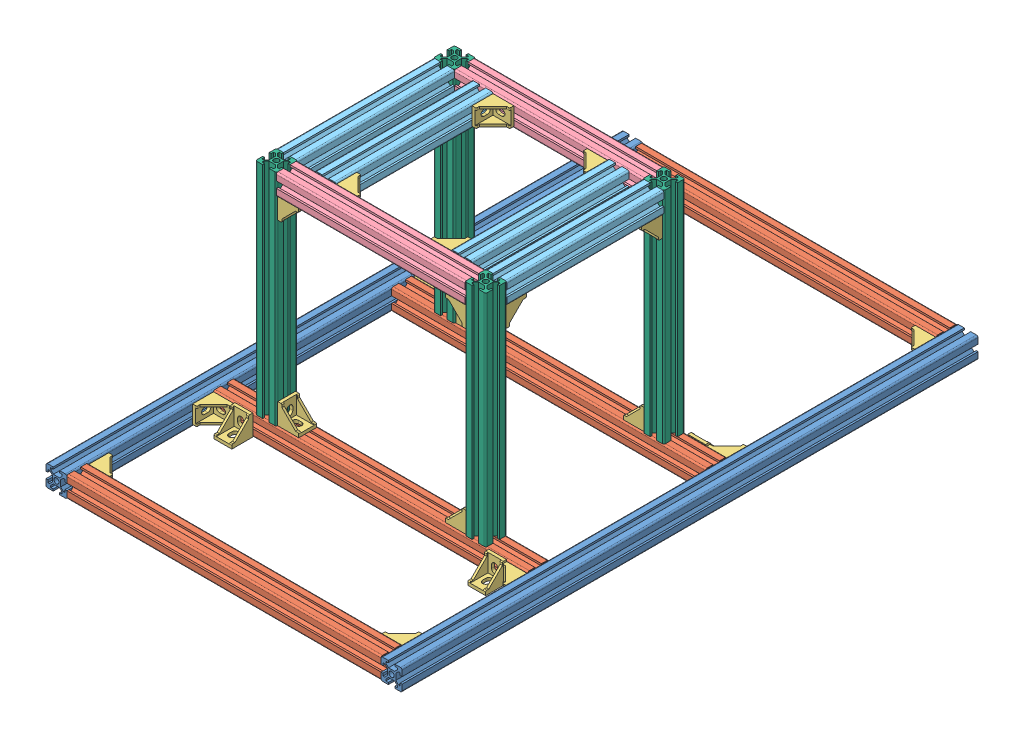
SolidWorks assembly 外框架, configuration 默认. Lengths in mm.
Overall size (340 230 550).
44 component instances, 6 part files, 128 mates.
Components (placement in the parent):
- 20x20-550mm-1: 20x20-550mm [默认] at (125.4634 0 -275) x (-1 0 0) z (0 0 -1) size (20 20 550)
- 20x20-550mm-2: 20x20-550mm [默认] at (-194.5366 0 -275) x (-1 0 0) z (0 0 -1) size (20 20 550)
- 20x20-300mm-1: 20x20-300mm [默认] at (115.4634 0 -265) x (0 0 -1) z (1 0 0) size (20 20 300)
- 20x20-300mm-2: 20x20-300mm [默认] at (115.4634 0 265) x (0 0 -1) z (1 0 0) size (20 20 300)
- 20x20-300mm-4: 20x20-300mm [默认] at (115.4634 0 125) x (0 0 -1) z (1 0 0) size (20 20 300)
- 20x20-300mm-5: 20x20-300mm [默认] at (115.4634 0 -45) x (0 0 -1) z (1 0 0) size (20 20 300)
- 2020 Corner pieces-1: 2020 Corner pieces [默认] at (55.4634 190 -44.8) x (0 0 1) z (0 -1 0) size (17 20 20)
- 2020-210mm-1: 2020-210mm [默认] at (-124.5366 210 -45) x (0 0 1) z (-1 0 0) size (20 20 180)
- 20x20-150mm-1: 20x20-150mm [默认] at (-134.5366 210 -35) x (0 1 0) z (0 0 -1) size (20 20 150)
- 2020 Corner pieces-2: 2020 Corner pieces [默认] at (-124.5366 190 -44.8) x (0 0 -1) z (0 -1 0) size (17 20 20)
- 2020 Corner pieces-3: 2020 Corner pieces [默认] at (-134.3366 190 -35) x (1 0 0) z (0 -1 0) size (17 20 20)
- 2020 Corner pieces-4: 2020 Corner pieces [默认] at (-134.3366 190 115) x (-1 0 0) z (0 -1 0) size (17 20 20)
- 2020 Corner pieces-5: 2020 Corner pieces [默认] at (-124.5366 190 125.2) x (0 0 -1) z (0 -1 0) size (17 20 20)
- 2020-210mm-2: 2020-210mm [默认] at (-124.5366 210 125) x (0 0 1) z (-1 0 0) size (20 20 180)
- 2020 Corner pieces-6: 2020 Corner pieces [默认] at (55.4634 190 125.2) x (0 0 1) z (0 -1 0) size (17 20 20)
- 2020 Corner pieces-7: 2020 Corner pieces [默认] at (65.6634 190 115) x (-1 0 0) z (0 -1 0) size (17 20 20)
- 20x20-150mm-2: 20x20-150mm [默认] at (65.4634 210 -35) x (0 1 0) z (0 0 -1) size (20 20 150)
- 2020 Corner pieces-8: 2020 Corner pieces [默认] at (65.6634 190 -35) x (1 0 0) z (0 -1 0) size (17 20 20)
- 2020 Corner pieces-9: 2020 Corner pieces [默认] at (45.4634 10 125.2) x (0 0 1) z (-1 0 0) size (17 20 20)
- 2020 Corner pieces-10: 2020 Corner pieces [默认] at (45.4634 10 -44.8) x (0 0 1) z (-1 0 0) size (17 20 20)
- 2020 Corner pieces-11: 2020 Corner pieces [默认] at (115.4634 -0.2 -65) x (0 -1 0) z (0 0 -1) size (17 20 20)
- 2020 Corner pieces-12: 2020 Corner pieces [默认] at (-124.5366 20 125.2) x (0 0 1) z (0 1 0) size (17 20 20)
- 2020 Corner pieces-13: 2020 Corner pieces [默认] at (115.4634 -0.2 145) x (0 1 0) z (0 0 1) size (17 20 20)
- 2020 Corner pieces-14: 2020 Corner pieces [默认] at (-184.5366 -0.2 -65) x (0 1 0) z (0 0 -1) size (17 20 20)
- 2020 Corner pieces-15: 2020 Corner pieces [默认] at (-124.5366 20 -44.8) x (0 0 1) z (0 1 0) size (17 20 20)
- 2020 Corner pieces-16: 2020 Corner pieces [默认] at (-184.5366 -0.2 -245) x (0 -1 0) z (0 0 1) size (17 20 20)
- 2020 Corner pieces-17: 2020 Corner pieces [默认] at (105.4634 0.2 -255) x (0 -1 0) z (-1 0 0) size (17 20 20)
- 20x20-150mm-3: 20x20-150mm [默认] at (32.3019 210 -35) x (1 0 0) z (0 0 -1) size (20 20 150)
- 2020 Corner pieces-18: 2020 Corner pieces [默认] at (12.3019 209.8 115) x (0 1 0) z (-1 0 0) size (17 20 20)
- 2020 Corner pieces-19: 2020 Corner pieces [默认] at (12.3019 209.8 -35) x (0 -1 0) z (-1 0 0) size (17 20 20)
- 20x20-150mm-4: 20x20-150mm [默认] at (-97.6981 210 -35) x (-1 0 0) z (0 0 -1) size (20 20 150)
- 2020 Corner pieces-20: 2020 Corner pieces [默认] at (-77.6981 210.2 115) x (0 -1 0) z (1 0 0) size (17 20 20)
- 2020 Corner pieces-21: 2020 Corner pieces [默认] at (-77.6981 210.2 -35) x (0 1 0) z (1 0 0) size (17 20 20)
- 2020 Corner pieces-22: 2020 Corner pieces [默认] at (-155.5864 -10 -65) x (-1 0 0) z (0 0 -1) size (17 20 20)
- 2020 Corner pieces-23: 2020 Corner pieces [默认] at (-155.5864 -10 145) size (17 20 20)
- 2020 Corner pieces-24: 2020 Corner pieces [默认] at (86.8158 -10 145) size (17 20 20)
- 2020 Corner pieces-25: 2020 Corner pieces [默认] at (-184.5366 -0.2 245) x (0 1 0) z (0 0 -1) size (17 20 20)
- 2020 Corner pieces-26: 2020 Corner pieces [默认] at (105.4634 -0.2 255) x (0 1 0) z (-1 0 0) size (17 20 20)
- 2020 Corner pieces-27: 2020 Corner pieces [默认] at (86.8158 -10 -65) x (-1 0 0) z (0 0 -1) size (17 20 20)
- 2020 Corner pieces-28: 2020 Corner pieces [默认] at (-184.5366 0.2 145) x (0 -1 0) z (0 0 1) size (17 20 20)
- 20x20-250mm-1: 20x20-250mm [默认] at (65.4634 220 125) x (0 0 -1) z (0 1 0) size (20 20 210)
- 20x20-250mm-2: 20x20-250mm [默认] at (-134.5366 220 125) x (1 0 0) z (0 1 0) size (20 20 210)
- 20x20-250mm-3: 20x20-250mm [默认] at (65.4634 220 -45) x (1 0 0) z (0 1 0) size (20 20 210)
- 20x20-250mm-4: 20x20-250mm [默认] at (-134.5366 220 -45) x (1 0 0) z (0 1 0) size (20 20 210)
Mates (geometry in assembly coordinates):
- 重合1: coincident anti-aligned: plane of 20x20-550mm-1 through (115.4634 -8.5 275) normal (-1 0 0); plane of 20x20-300mm-1 through (115.4634 -8.5 -273.5) normal (1 0 0)
- 重合2: coincident aligned: plane of 20x20-550mm-1 through (133.9634 10 275) normal (0 1 0); plane of 20x20-300mm-1 through (-184.5366 10 -256.5) normal (0 1 0)
- 重合3: coincident anti-aligned: plane of 20x20-550mm-2 through (-184.5366 3.1 275) normal (1 0 0); plane of 20x20-300mm-1 through (-184.5366 -8.5 -273.5) normal (-1 0 0)
- 重合4: coincident aligned: plane of 20x20-550mm-2 through (-186.0366 10 275) normal (0 1 0); plane of 20x20-300mm-1 through (-184.5366 10 -268.1) normal (0 1 0)
- 重合5: coincident aligned: plane of 20x20-550mm-2 through (-203.0366 -8.5 -275) normal (0 0 -1); plane of 20x20-300mm-1 through (-184.5366 -8.5 -275) normal (0 0 -1)
- 重合6: coincident aligned: plane of 20x20-550mm-1 through (116.9634 -8.5 -275) normal (0 0 -1); plane of 20x20-550mm-2 through (-203.0366 -8.5 -275) normal (0 0 -1)
- 重合7: coincident anti-aligned: plane of 20x20-550mm-1 through (115.4634 -8.5 275) normal (-1 0 0); plane of 20x20-300mm-5 through (115.4634 -8.5 -133.5) normal (1 0 0)
- 重合8: coincident aligned: plane of 20x20-300mm-1 through (-184.5366 10 -256.5) normal (0 1 0); plane of 20x20-300mm-5 through (-184.5366 10 -128.1) normal (0 1 0)
- 重合9: coincident anti-aligned: plane of 20x20-550mm-1 through (115.4634 -8.5 275) normal (-1 0 0); plane of 20x20-300mm-2 through (115.4634 -8.5 256.5) normal (1 0 0)
- 重合10: coincident aligned: plane of 20x20-300mm-2 through (-184.5366 10 273.5) normal (0 1 0); plane of 20x20-300mm-5 through (-184.5366 10 -116.5) normal (0 1 0)
- 重合11: coincident anti-aligned: plane of 20x20-550mm-1 through (115.4634 -8.5 275) normal (-1 0 0); plane of 20x20-300mm-4 through (115.4634 -8.5 36.5) normal (1 0 0)
- 重合12: coincident aligned: plane of 20x20-550mm-1 through (122.3634 10 275) normal (0 1 0); plane of 20x20-300mm-4 through (-184.5366 10 53.5) normal (0 1 0)
- 重合13: coincident aligned: plane of 20x20-550mm-1 through (116.9634 -8.5 275) normal (0 0 1); plane of 20x20-300mm-2 through (-184.5366 -8.5 275) normal (0 0 1)
- 重合22: coincident anti-aligned: plane of 2020 Corner pieces-1 through (35.4634 200 -133.3) normal (0 1 0); plane of 2020-210mm-1 through (55.4634 200 -121.9) normal (0 -1 0)
- 重合23: coincident aligned: plane of 2020 Corner pieces-1 through (55.4634 190 -124.8) normal (1 0 0); plane of 2020-210mm-1 through (55.4634 201.5 -116.5) normal (1 0 0)
- 重合24: coincident anti-aligned: plane of 2020-210mm-1 through (55.4634 200 -133.5) normal (0 -1 0); plane of 2020 Corner pieces-2 through (-104.5366 200 -116.3) normal (0 1 0)
- 重合25: coincident aligned: plane of 2020-210mm-1 through (-124.5366 201.5 -116.5) normal (-1 0 0); plane of 2020 Corner pieces-2 through (-124.5366 190 -124.8) normal (-1 0 0)
- 重合26: coincident anti-aligned: plane of 20x20-150mm-1 through (-131.4366 200 35) normal (0 -1 0); plane of 2020 Corner pieces-4 through (-125.8366 200 15) normal (0 1 0)
- 重合27: coincident aligned: plane of 20x20-150mm-1 through (-143.0366 218.5 35) normal (0 0 1); plane of 2020 Corner pieces-4 through (-134.3366 190 35) normal (0 0 1)
- 重合28: coincident aligned: plane of 20x20-150mm-1 through (-131.4366 201.8 35) normal (-1 0 0); plane of 2020 Corner pieces-4 through (-131.4366 200 26.5) normal (-1 0 0)
- 重合29: coincident anti-aligned: plane of 20x20-150mm-1 through (-131.4366 200 35) normal (0 -1 0); plane of 2020 Corner pieces-3 through (-142.8366 200 -95) normal (0 1 0)
- 重合30: coincident aligned: plane of 20x20-150mm-1 through (-143.0366 218.5 -115) normal (0 0 -1); plane of 2020 Corner pieces-3 through (-134.3366 190 -115) normal (0 0 -1)
- 重合31: coincident aligned: plane of 20x20-150mm-1 through (-131.4366 201.8 35) normal (-1 0 0); plane of 2020 Corner pieces-3 through (-131.4366 200 -103.5) normal (-1 0 0)
- 重合32: coincident aligned: plane of 2020-210mm-2 through (55.4634 201.5 53.5) normal (1 0 0); plane of 2020 Corner pieces-6 through (55.4634 190 45.2) normal (1 0 0)
- 重合33: coincident anti-aligned: plane of 2020-210mm-2 through (55.4634 200 48.1) normal (0 -1 0); plane of 2020 Corner pieces-6 through (35.4634 200 36.7) normal (0 1 0)
- 重合34: coincident anti-aligned: plane of 2020 Corner pieces-5 through (-104.5366 200 53.7) normal (0 1 0); plane of 2020-210mm-2 through (55.4634 200 36.5) normal (0 -1 0)
- 重合35: coincident aligned: plane of 2020 Corner pieces-5 through (-124.5366 190 45.2) normal (-1 0 0); plane of 2020-210mm-2 through (-124.5366 201.5 53.5) normal (-1 0 0)
- 重合36: coincident aligned: plane of 2020 Corner pieces-7 through (68.5634 200 26.5) normal (-1 0 0); plane of 20x20-150mm-2 through (68.5634 201.8 35) normal (-1 0 0)
- 重合37: coincident anti-aligned: plane of 2020 Corner pieces-7 through (74.1634 200 15) normal (0 1 0); plane of 20x20-150mm-2 through (68.5634 200 35) normal (0 -1 0)
- 重合38: coincident aligned: plane of 2020 Corner pieces-7 through (65.6634 190 35) normal (0 0 1); plane of 20x20-150mm-2 through (56.9634 218.5 35) normal (0 0 1)
- 重合39: coincident anti-aligned: plane of 20x20-150mm-2 through (68.5634 200 35) normal (0 -1 0); plane of 2020 Corner pieces-8 through (57.1634 200 -95) normal (0 1 0)
- 重合40: coincident aligned: plane of 20x20-150mm-2 through (56.9634 218.5 -115) normal (0 0 -1); plane of 2020 Corner pieces-8 through (65.6634 190 -115) normal (0 0 -1)
- 重合41: coincident aligned: plane of 20x20-150mm-2 through (68.5634 201.8 35) normal (-1 0 0); plane of 2020 Corner pieces-8 through (68.5634 200 -103.5) normal (-1 0 0)
- 重合48: coincident aligned: plane of 20x20-150mm-1 through (-143.0366 220 35) normal (0 1 0); plane of 20x20-150mm-2 through (56.9634 220 35) normal (0 1 0)
- 重合52: coincident: plane of 2020 Corner pieces-1 through (43.9634 200 -121.9) normal (0 0 -1); line of 2020-210mm-1 through (55.4634 201.8 -121.9) axis (-1 0 0)
- 重合55: coincident aligned: plane of 2020-210mm-1 through (55.4634 201.8 -121.9) normal (0 0 -1); plane of 2020 Corner pieces-2 through (-116.0366 200 -121.9) normal (0 0 -1)
- 重合57: coincident aligned: plane of 2020-210mm-2 through (55.4634 201.8 48.1) normal (0 0 -1); plane of 2020 Corner pieces-6 through (43.9634 200 48.1) normal (0 0 -1)
- 重合59: coincident aligned: plane of 2020 Corner pieces-5 through (-116.0366 200 48.1) normal (0 0 -1); plane of 2020-210mm-2 through (55.4634 201.8 48.1) normal (0 0 -1)
- 重合61: coincident aligned: plane of 20x20-550mm-1 through (125.4634 0 -275) normal (0 1 0)
- 距离1: distance = 275 mm: plane of assembly through (0 0 0) normal (0 0 1); plane of assembly; plane of 20x20-550mm-1 through (125.4634 0 -275) normal (0 0 -1)
- 重合62: coincident anti-aligned: plane of 20x20-550mm-1 through (115.4634 3.1 275) normal (-1 0 0); plane of 2020 Corner pieces-17 through (115.4634 8.7 -235) normal (1 0 0)
- 重合63: coincident anti-aligned: plane of 20x20-300mm-1 through (-184.5366 -8.5 -255) normal (0 0 1); plane of 2020 Corner pieces-17 through (105.4634 0.2 -255) normal (0 0 -1)
- 重合64: coincident aligned: plane of 20x20-550mm-1 through (117.2634 3.1 275) normal (0 -1 0); plane of 2020 Corner pieces-17 through (115.4634 3.1 -246.5) normal (0 -1 0)
- 重合65: coincident anti-aligned: plane of 20x20-300mm-1 through (-184.5366 3.1 -255) normal (0 0 1); plane of 2020 Corner pieces-16 through (-164.5366 8.3 -255) normal (0 0 -1)
- 重合66: coincident anti-aligned: plane of 20x20-550mm-2 through (-184.5366 3.1 275) normal (1 0 0); plane of 2020 Corner pieces-16 through (-184.5366 -0.2 -245) normal (-1 0 0)
- 重合67: coincident aligned: plane of 20x20-550mm-2 through (-186.3366 -3.1 275) normal (0 1 0); plane of 2020 Corner pieces-16 through (-184.5366 -3.1 -246.5) normal (0 1 0)
- 重合68: coincident anti-aligned: plane of 20x20-300mm-5 through (-184.5366 3.1 -135) normal (0 0 -1); plane of 2020 Corner pieces-11 through (95.4634 8.3 -135) normal (0 0 1)
- 重合69: coincident anti-aligned: plane of 20x20-550mm-1 through (115.4634 -8.5 275) normal (-1 0 0); plane of 2020 Corner pieces-11 through (115.4634 -0.2 -145) normal (1 0 0)
- 重合73: coincident aligned: plane of 20x20-300mm-5 through (-184.5366 -3.1 -133.2) normal (0 1 0); plane of 2020 Corner pieces-11 through (103.9634 -3.1 -135) normal (0 1 0)
- 重合75: coincident anti-aligned: plane of 20x20-300mm-5 through (-184.5366 10 -116.5) normal (0 1 0); plane of 2020 Corner pieces-10 through (45.4634 10 -124.8) normal (0 -1 0)
- 重合76: coincident aligned: plane of 20x20-300mm-5 through (-184.5366 8.2 -121.9) normal (0 0 -1); plane of 2020 Corner pieces-10 through (46.9634 10 -121.9) normal (0 0 -1)
- 重合77: coincident anti-aligned: plane of 20x20-300mm-5 through (-184.5366 -8.5 -135) normal (0 0 -1); plane of 2020 Corner pieces-14 through (-164.5366 -8.7 -135) normal (0 0 1)
- 重合78: coincident anti-aligned: plane of 20x20-550mm-2 through (-184.5366 3.1 275) normal (1 0 0); plane of 2020 Corner pieces-14 through (-184.5366 -0.2 -145) normal (-1 0 0)
- 重合79: coincident aligned: plane of 20x20-300mm-5 through (-184.5366 -3.1 -133.2) normal (0 1 0); plane of 2020 Corner pieces-14 through (-176.0366 -3.1 -135) normal (0 1 0)
- 重合80: coincident anti-aligned: plane of 20x20-300mm-5 through (-184.5366 10 -128.1) normal (0 1 0); plane of 2020 Corner pieces-15 through (-104.5366 10 -133.3) normal (0 -1 0)
- 重合82: coincident aligned: plane of 20x20-300mm-5 through (-184.5366 8.2 -121.9) normal (0 0 -1); plane of 2020 Corner pieces-15 through (-113.0366 10 -121.9) normal (0 0 -1)
- 重合84: coincident anti-aligned: plane of 20x20-300mm-4 through (-184.5366 10 41.9) normal (0 1 0); plane of 2020 Corner pieces-9 through (45.4634 10 45.2) normal (0 -1 0)
- 重合86: coincident anti-aligned: plane of 20x20-300mm-4 through (-184.5366 10 53.5) normal (0 1 0); plane of 2020 Corner pieces-12 through (-104.5366 10 36.7) normal (0 -1 0)
- 重合88: coincident aligned: plane of 20x20-300mm-4 through (-184.5366 8.2 48.1) normal (0 0 -1); plane of 2020 Corner pieces-12 through (-113.0366 10 48.1) normal (0 0 -1)
- 重合89: coincident anti-aligned: plane of 20x20-300mm-4 through (-184.5366 -8.5 55) normal (0 0 1); plane of 2020 Corner pieces-13 through (95.4634 -8.7 55) normal (0 0 -1)
- 重合90: coincident anti-aligned: plane of 20x20-550mm-1 through (115.4634 -8.5 275) normal (-1 0 0); plane of 2020 Corner pieces-13 through (115.4634 -0.2 65) normal (1 0 0)
- 重合91: coincident aligned: plane of 20x20-300mm-4 through (-184.5366 -3.1 53.2) normal (0 1 0); plane of 2020 Corner pieces-13 through (106.9634 -3.1 55) normal (0 1 0)
- 重合92: coincident anti-aligned: plane of 20x20-150mm-3 through (22.3019 206.9 35) normal (-1 0 0); plane of 2020 Corner pieces-18 through (22.3019 201.3 15) normal (1 0 0)
- 重合93: coincident aligned: plane of 20x20-150mm-3 through (24.1019 206.9 35) normal (0 1 0); plane of 2020 Corner pieces-18 through (22.3019 206.9 26.5) normal (0 1 0)
- 重合94: coincident aligned: plane of 20x20-150mm-3 through (40.8019 218.5 -115) normal (0 0 -1); plane of 2020 Corner pieces-19 through (12.3019 209.8 -115) normal (0 0 -1)
- 重合95: coincident aligned: plane of 20x20-150mm-3 through (40.8019 218.5 35) normal (0 0 1); plane of 2020 Corner pieces-18 through (12.3019 209.8 35) normal (0 0 1)
- 重合96: coincident aligned: plane of 20x20-150mm-3 through (24.1019 206.9 35) normal (0 1 0); plane of 2020 Corner pieces-19 through (22.3019 206.9 -103.5) normal (0 1 0)
- 重合97: coincident anti-aligned: plane of 20x20-150mm-3 through (22.3019 206.9 35) normal (-1 0 0); plane of 2020 Corner pieces-19 through (22.3019 218.3 -95) normal (1 0 0)
- 重合98: coincident anti-aligned: plane of 20x20-150mm-4 through (-87.6981 213.1 35) normal (1 0 0); plane of 2020 Corner pieces-20 through (-87.6981 218.7 15) normal (-1 0 0)
- 重合99: coincident aligned: plane of 20x20-150mm-4 through (-89.4981 213.1 35) normal (0 -1 0); plane of 2020 Corner pieces-20 through (-87.6981 213.1 26.5) normal (0 -1 0)
- 重合100: coincident aligned: plane of 20x20-150mm-4 through (-106.1981 201.5 -115) normal (0 0 -1); plane of 2020 Corner pieces-21 through (-77.6981 210.2 -115) normal (0 0 -1)
- 重合101: coincident aligned: plane of 20x20-150mm-4 through (-106.1981 201.5 35) normal (0 0 1); plane of 2020 Corner pieces-20 through (-77.6981 210.2 35) normal (0 0 1)
- 重合102: coincident aligned: plane of 20x20-150mm-4 through (-89.4981 213.1 35) normal (0 -1 0); plane of 2020 Corner pieces-21 through (-87.6981 213.1 -103.5) normal (0 -1 0)
- 重合103: coincident anti-aligned: plane of 20x20-150mm-4 through (-87.6981 213.1 35) normal (1 0 0); plane of 2020 Corner pieces-21 through (-87.6981 201.7 -95) normal (-1 0 0)
- 重合104: coincident anti-aligned: plane of 2020-210mm-1 through (55.4634 213.1 -115) normal (0 0 1); plane of 20x20-150mm-4 through (-106.1981 201.5 -115) normal (0 0 -1)
- 重合105: coincident aligned: plane of 2020-210mm-1 through (55.4634 220 -121.9) normal (0 1 0); plane of 20x20-150mm-4 through (-89.1981 220 35) normal (0 1 0)
- 重合106: coincident anti-aligned: plane of 2020-210mm-1 through (55.4634 213.1 -115) normal (0 0 1); plane of 20x20-150mm-3 through (40.8019 218.5 -115) normal (0 0 -1)
- 重合107: coincident aligned: plane of 2020-210mm-1 through (55.4634 220 -121.9) normal (0 1 0); plane of 20x20-150mm-3 through (23.8019 220 35) normal (0 1 0)
- 重合108: coincident aligned: plane of 2020-210mm-1 through (55.4634 220 -133.5) normal (0 1 0); plane of 2020-210mm-2 through (55.4634 220 36.5) normal (0 1 0)
- 重合109: coincident anti-aligned: plane of 20x20-300mm-4 through (-184.5366 -8.5 55) normal (0 0 1); plane of 2020 Corner pieces-28 through (-164.5366 8.7 55) normal (0 0 -1)
- 重合110: coincident anti-aligned: plane of 20x20-550mm-2 through (-184.5366 -8.5 275) normal (1 0 0); plane of 2020 Corner pieces-28 through (-184.5366 0.2 65) normal (-1 0 0)
- 重合111: coincident aligned: plane of 20x20-550mm-2 through (-186.3366 3.1 275) normal (0 -1 0); plane of 2020 Corner pieces-28 through (-184.5366 3.1 66.5) normal (0 -1 0)
- 重合112: coincident anti-aligned: plane of 20x20-300mm-2 through (-184.5366 3.1 255) normal (0 0 -1); plane of 2020 Corner pieces-25 through (-164.5366 -8.7 255) normal (0 0 1)
- 重合113: coincident anti-aligned: plane of 20x20-550mm-2 through (-184.5366 3.1 275) normal (1 0 0); plane of 2020 Corner pieces-25 through (-184.5366 -0.2 245) normal (-1 0 0)
- 重合114: coincident aligned: plane of 20x20-550mm-2 through (-186.3366 -3.1 275) normal (0 1 0); plane of 2020 Corner pieces-25 through (-184.5366 -3.1 243.5) normal (0 1 0)
- 重合115: coincident anti-aligned: plane of 20x20-550mm-1 through (115.4634 3.1 275) normal (-1 0 0); plane of 2020 Corner pieces-26 through (115.4634 -8.7 235) normal (1 0 0)
- 重合116: coincident anti-aligned: plane of 20x20-300mm-2 through (-184.5366 3.1 255) normal (0 0 -1); plane of 2020 Corner pieces-26 through (105.4634 -0.2 255) normal (0 0 1)
- 重合117: coincident aligned: plane of 20x20-550mm-1 through (117.2634 -3.1 275) normal (0 1 0); plane of 2020 Corner pieces-26 through (115.4634 -3.1 246.5) normal (0 1 0)
- 重合118: coincident anti-aligned: plane of 20x20-300mm-4 through (-184.5366 -8.5 55) normal (0 0 1); plane of 2020 Corner pieces-24 through (78.3158 10 55) normal (0 0 -1)
- 重合121: coincident aligned: plane of 20x20-300mm-4 through (-184.5366 -10 53.5) normal (0 -1 0); plane of 2020 Corner pieces-24 through (86.8158 -10 65) normal (0 -1 0)
- 重合122: coincident anti-aligned: plane of 20x20-300mm-4 through (-184.5366 -8.5 55) normal (0 0 1); plane of 2020 Corner pieces-23 through (-164.0864 10 55) normal (0 0 -1)
- 重合123: coincident aligned: plane of 20x20-300mm-4 through (-184.5366 -10 53.5) normal (0 -1 0); plane of 2020 Corner pieces-23 through (-155.5864 -10 65) normal (0 -1 0)
- 重合124: coincident anti-aligned: plane of 20x20-300mm-5 through (-184.5366 3.1 -135) normal (0 0 -1); plane of 2020 Corner pieces-22 through (-147.0864 10 -135) normal (0 0 1)
- 重合125: coincident aligned: plane of 20x20-300mm-5 through (-184.5366 -10 -128.1) normal (0 -1 0); plane of 2020 Corner pieces-22 through (-155.5864 -10 -145) normal (0 -1 0)
- 重合126: coincident aligned: plane of 2020 Corner pieces-22 through (-164.0864 10 -155) normal (-1 0 0); plane of 2020 Corner pieces-23 through (-164.0864 10 75) normal (-1 0 0)
- 重合127: coincident anti-aligned: plane of 20x20-300mm-5 through (-184.5366 3.1 -135) normal (0 0 -1); plane of 2020 Corner pieces-27 through (95.3158 10 -135) normal (0 0 1)
- 重合128: coincident aligned: plane of 20x20-300mm-5 through (-184.5366 -10 -128.1) normal (0 -1 0); plane of 2020 Corner pieces-27 through (86.8158 -10 -145) normal (0 -1 0)
- 重合129: coincident aligned: plane of 2020 Corner pieces-24 through (95.3158 10 75) normal (1 0 0); plane of 2020 Corner pieces-27 through (95.3158 10 -155) normal (1 0 0)
- 重合130: coincident anti-aligned: plane of 2020-210mm-2 through (55.4634 201.5 53.5) normal (1 0 0); plane of 20x20-250mm-1 through (55.4634 10 41.9) normal (-1 0 0)
- 重合131: coincident anti-aligned: plane of 20x20-300mm-4 through (-184.5366 10 41.9) normal (0 1 0); plane of 20x20-250mm-1 through (73.9634 10 36.5) normal (0 -1 0)
- 重合132: coincident aligned: plane of 2020-210mm-2 through (55.4634 201.5 35) normal (0 0 -1); plane of 20x20-250mm-1 through (62.3634 10 35) normal (0 0 -1)
- 重合133: coincident anti-aligned: plane of 20x20-300mm-5 through (-184.5366 10 -128.1) normal (0 1 0); plane of 20x20-250mm-3 through (73.9634 10 -116.5) normal (0 -1 0)
- 重合134: coincident aligned: plane of 20x20-300mm-5 through (-184.5366 3.1 -135) normal (0 0 -1); plane of 20x20-250mm-3 through (68.5634 10 -135) normal (0 0 -1)
- 重合135: coincident anti-aligned: plane of 2020 Corner pieces-10 through (55.4634 30 -133.3) normal (1 0 0); plane of 20x20-250mm-3 through (55.4634 10 -116.5) normal (-1 0 0)
- 重合136: coincident anti-aligned: plane of 20x20-300mm-4 through (-184.5366 10 41.9) normal (0 1 0); plane of 20x20-250mm-2 through (-126.0366 10 53.5) normal (0 -1 0)
- 重合137: coincident anti-aligned: plane of 2020 Corner pieces-12 through (-124.5366 20 45.2) normal (-1 0 0); plane of 20x20-250mm-2 through (-124.5366 10 41.9) normal (1 0 0)
- 重合138: coincident aligned: plane of 20x20-300mm-4 through (-184.5366 3.1 35) normal (0 0 -1); plane of 20x20-250mm-2 through (-131.4366 10 35) normal (0 0 -1)
- 重合139: coincident anti-aligned: plane of 20x20-300mm-5 through (-184.5366 10 -128.1) normal (0 1 0); plane of 20x20-250mm-4 through (-126.0366 10 -116.5) normal (0 -1 0)
- 重合140: coincident aligned: plane of 20x20-300mm-5 through (-184.5366 3.1 -135) normal (0 0 -1); plane of 20x20-250mm-4 through (-143.0366 10 -135) normal (0 0 -1)
- 重合141: coincident anti-aligned: plane of 2020 Corner pieces-15 through (-124.5366 20 -124.8) normal (-1 0 0); plane of 20x20-250mm-4 through (-124.5366 10 -128.1) normal (1 0 0)
- 重合142: coincident aligned: plane of 20x20-150mm-1 through (-143.0366 220 35) normal (0 1 0); plane of 20x20-250mm-4 through (-126.0366 220 -116.5) normal (0 1 0)
- 重合143: coincident aligned: plane of 2020-210mm-1 through (55.4634 220 -133.5) normal (0 1 0); plane of 20x20-250mm-4 through (-126.0366 220 -116.5) normal (0 1 0)
- 重合144: coincident anti-aligned: plane of 20x20-150mm-2 through (56.9634 218.5 -115) normal (0 0 -1); plane of 20x20-250mm-3 through (56.9634 10 -115) normal (0 0 1)
- 重合145: coincident anti-aligned: plane of 20x20-150mm-2 through (56.9634 218.5 35) normal (0 0 1); plane of 20x20-250mm-1 through (62.3634 10 35) normal (0 0 -1)
- 重合146: coincident anti-aligned: plane of 20x20-150mm-1 through (-143.0366 218.5 35) normal (0 0 1); plane of 20x20-250mm-2 through (-143.0366 10 35) normal (0 0 -1)
- 重合147: coincident anti-aligned: plane of 20x20-150mm-1 through (-143.0366 218.5 -115) normal (0 0 -1); plane of 20x20-250mm-4 through (-143.0366 10 -115) normal (0 0 1)
- 重合148: coincident anti-aligned: plane of 2020-210mm-1 through (-124.5366 201.5 -116.5) normal (-1 0 0); plane of 20x20-250mm-4 through (-124.5366 10 -128.1) normal (1 0 0)
- 重合149: coincident anti-aligned: plane of 2020-210mm-1 through (55.4634 201.5 -116.5) normal (1 0 0); plane of 20x20-250mm-3 through (55.4634 10 -128.1) normal (-1 0 0)
- 重合150: coincident aligned: plane of 20x20-150mm-2 through (75.4634 201.5 35) normal (1 0 0); plane of 20x20-250mm-3 through (75.4634 10 -116.5) normal (1 0 0)
- 重合151: coincident aligned: plane of 20x20-150mm-2 through (75.4634 213.1 35) normal (1 0 0); plane of 20x20-250mm-1 through (75.4634 10 41.9) normal (1 0 0)
- 重合152: coincident aligned: plane of 20x20-150mm-1 through (-144.5366 213.1 35) normal (-1 0 0); plane of 20x20-250mm-4 through (-144.5366 10 -116.5) normal (-1 0 0)
- 重合153: coincident anti-aligned: plane of 2020-210mm-2 through (-124.5366 201.5 53.5) normal (-1 0 0); plane of 20x20-250mm-2 through (-124.5366 10 41.9) normal (1 0 0)
- 宽度3: width anti-aligned: plane of 20x20-550mm-1 through (135.4634 3.1 275) normal (1 0 0); plane of 20x20-550mm-2 through (-204.5366 3.1 275) normal (-1 0 0); plane of 20x20-250mm-4 through (-144.5366 10 -128.1) normal (-1 0 0); plane of 20x20-250mm-3 through (75.4634 10 -128.1) normal (1 0 0)
- 重合154: coincident aligned: plane of 2020-210mm-1 through (55.4634 213.1 -135) normal (0 0 -1); plane of 20x20-250mm-4 through (-131.4366 10 -135) normal (0 0 -1)
- 重合155: coincident anti-aligned: plane of 2020 Corner pieces-9 through (55.4634 30 36.7) normal (1 0 0); plane of 20x20-250mm-1 through (55.4634 10 53.5) normal (-1 0 0)
- 重合156: coincident aligned: plane of 2020 Corner pieces-9 through (35.4634 30 53.7) normal (0 0 1); plane of 2020 Corner pieces-12 through (-104.5366 30 53.7) normal (0 0 1)
- 距离2: distance = 110 mm anti-aligned: plane of 20x20-150mm-3 through (22.3019 218.5 115) normal (-1 0 0); plane of 20x20-150mm-4 through (-87.6981 213.1 115) normal (1 0 0)
- 距离4: distance = 200 mm anti-aligned: plane of 20x20-300mm-1 through (-184.5366 -8.5 -255) normal (0 0 1); plane of 20x20-300mm-5 through (-184.5366 3.1 -55) normal (0 0 -1)
